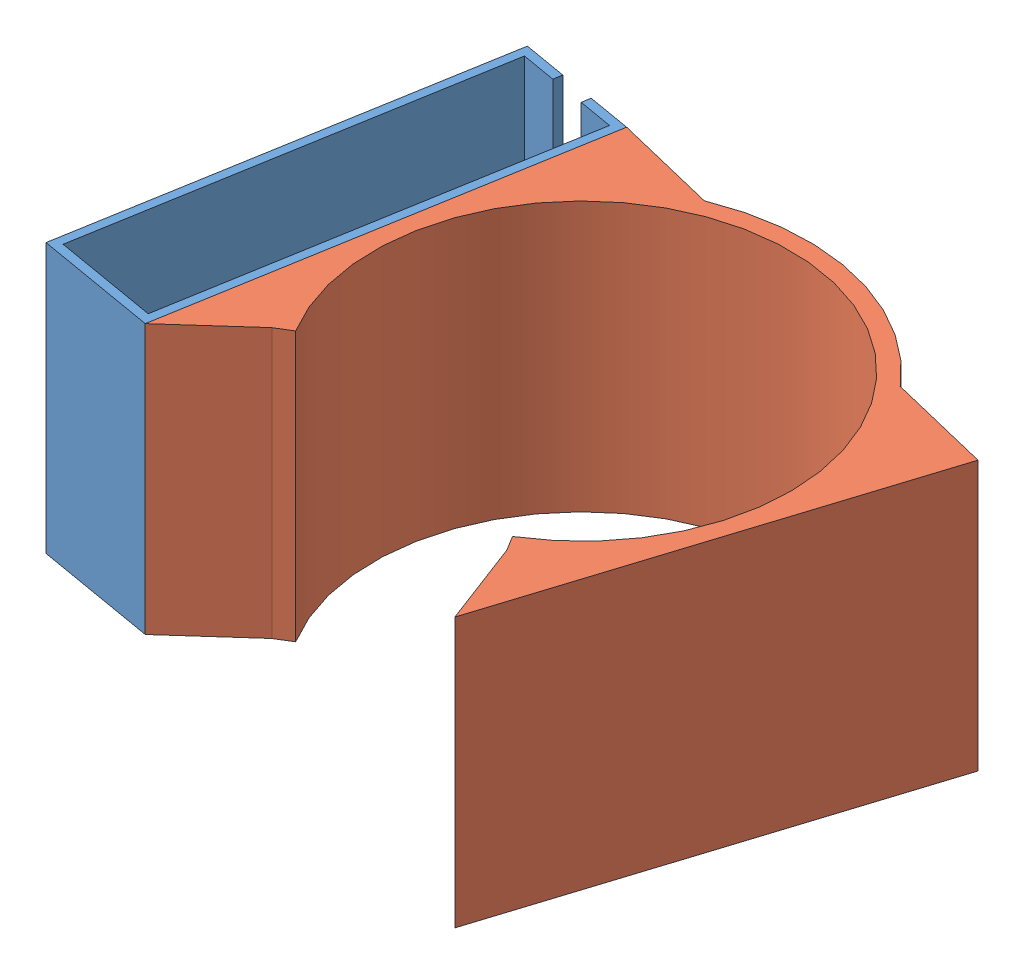
SolidWorks assembly shoe model 4.5, configuration Default. Lengths in mm.
Overall size (193.59 62 193.59).
2 component instances, 2 part files, 4 mates.
Components (placement in the parent):
- pi_holderSLDPRT-3: pi_holderSLDPRT [Default] at (185.9808 0 -126.2825) x (0.169261 0 -0.985571) z (0.985571 0 0.169261) size (96 62 28)
- cycle-3: cycle [Default] at (245.7535 0 -167.1085) x (0.854007 0 -0.520262) z (0.520262 0 0.854007) size (140.87 62 140.87)
Mates (geometry in assembly coordinates):
- Coincident7: coincident anti-aligned: plane of pi_holderSLDPRT-3 through (185.9808 62 -126.2825) normal (0.985571 0 0.169261); plane of cycle-3 through (185.9808 62 -126.2825) normal (-0.985571 0 -0.169261)
- Coincident8: coincident aligned: line of pi_holderSLDPRT-3 through (185.9808 62 -126.2825) axis (0 -1 0); line of cycle-3 through (185.9808 62 -126.2825) axis (0 -1 0)
- Coincident10: coincident anti-aligned: plane of cycle-3 through (245.7535 0 -167.1085) normal (0 -1 0)
- Coincident11: coincident anti-aligned: plane of pi_holderSLDPRT-3 through (185.9808 0 -126.2825) normal (0 -1 0)
